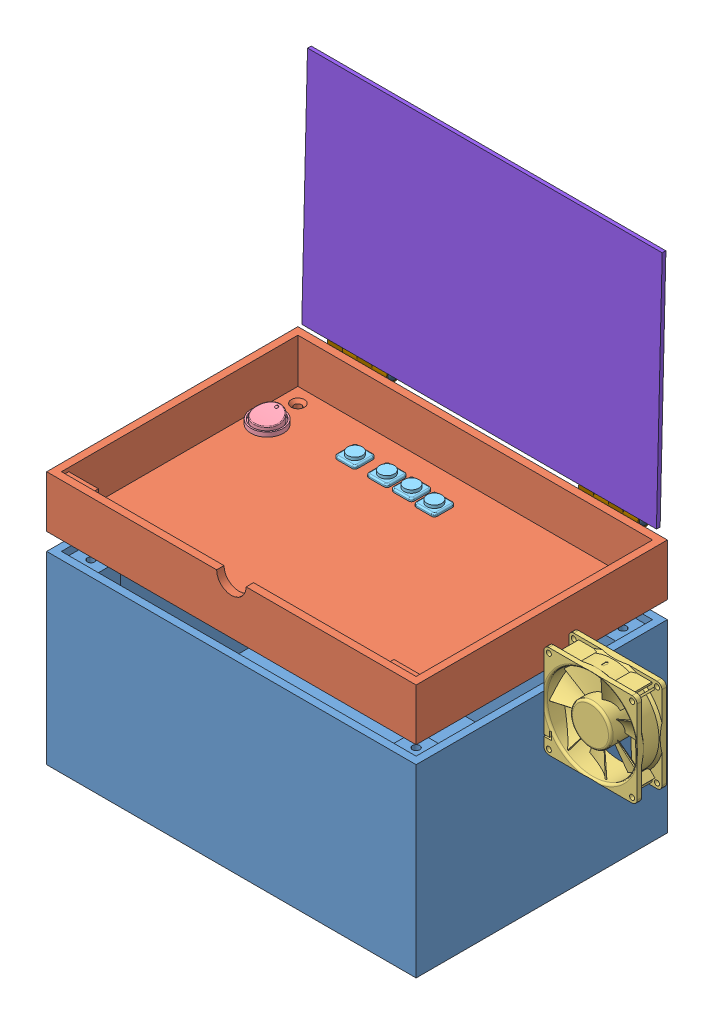
SolidWorks assembly Ground Station, configuration Default. Lengths in mm.
Overall size (498.71 464.43 236.08).
25 component instances, 10 part files, 22 mates.
Components (placement in the parent):
- Box-1: Box [Default] at (130.5013 73.7691 245.9058) size (317.5 158.75 215.9)
- Box Top-1: Box Top [Default] at (130.5013 241.0208 245.9058) size (317.5 50.8 215.9)
- Fan-1: Fan [Default] at (344.3941 242.0632 233.7635) size (80 80 25.71)
- LED Rocker Switch-1: LED Rocker Switch [Default] at (-7.1605 251.1808 185.4528) size (27.94 33 27.94)
- LED Pushbutton-1: LED Pushbutton [Default] at (104.5513 234.6708 173.1134) size (18 29.21 18)
- LED Pushbutton-2: LED Pushbutton [Default] at (83.4333 234.6708 173.1134) size (18 29.21 18)
- LED Pushbutton-3: LED Pushbutton [Default] at (125.7046 234.6708 174.5981) size (18 29.21 18)
- LED Pushbutton-4: LED Pushbutton [Default] at (55.9503 234.6708 173.1134) size (18 29.21 18)
- Green LED-1: Green LED [Default] at (-43.8115 97.7903 137.5598) size (5 11.66 5)
- Green LED-2: Green LED [Default] at (-40.7859 71.4501 137.6368) size (5 11.66 5)
- Green LED-3: Green LED [Default] at (-47.241 141.3846 137.4726) size (5 11.66 5)
- Green LED-4: Green LED [Default] at (-73.5588 134.6358 120.2712) size (5 11.66 5)
- Red LED-1: Red LED [Default] at (-32.75 69.0976 173.2575) size (5 11.66 5)
- Red LED-2: Red LED [Default] at (-48.8212 68.6997 187.7744) size (5 11.66 5)
- Red LED-3: Red LED [Default] at (-85.0237 38.2232 171.227) size (5 11.66 5)
- Red LED-4: Red LED [Default] at (-111.8171 51.6273 156.8365) size (5 11.66 5)
- Acrylic Cover-1: Acrylic Cover [Default] at (130.5013 399.8161 138.5042) x (1 0 0) z (0 0.999704 -0.02434) size (304.8 3.17 203.2)
- Hinge Assembly-1: Hinge Assembly [Default] at (14.4264 255.4915 156.4521) x (1 0 0) z (0 0.999704 -0.02434) size (55.88 13.47 50.95)
  - Hinge Piece-1: Hinge Piece [Default] at (8.1249 17.6047 53.2265) size (50.8 12.7 31.75)
  - Hinge Piece-2: Hinge Piece [Default] at (8.1249 18.0034 20.4703) x (-1 0 0) z (0 0.02434 -0.999704) size (50.8 12.7 31.75)
  - Hinge Pin-1: Hinge Pin [Default] at (-17.2751 23.9547 36.9233) x (0 0 -1) z (1 0 0) size (10.16 10.16 55.88)
- Hinge Assembly-2: Hinge Assembly [Default] at (230.3264 255.4915 156.4521) x (1 0 0) z (0 0.999704 -0.02434) size (55.88 13.47 50.95)
  - Hinge Piece-1: Hinge Piece [Default] at (8.1249 17.6047 53.2265) size (50.8 12.7 31.75)
  - Hinge Piece-2: Hinge Piece [Default] at (8.1249 18.0034 20.4703) x (-1 0 0) z (0 0.02434 -0.999704) size (50.8 12.7 31.75)
  - Hinge Pin-1: Hinge Pin [Default] at (-17.2751 23.9547 36.9233) x (0 0 -1) z (1 0 0) size (10.16 10.16 55.88)
Mates (geometry in assembly coordinates):
- Coincident1: coincident aligned: plane of Box-1 through (289.2513 80.1191 353.8558) normal (0 0 1); plane of Box Top-1 through (289.2513 253.7208 353.8558) normal (0 0 1)
- Coincident2: coincident aligned: plane of Box-1 through (-28.2487 80.1191 353.8558) normal (-1 0 0); plane of Box Top-1 through (-28.2487 253.7208 353.8558) normal (-1 0 0)
- Concentric1: concentric anti-aligned: cylinder of Box Top-1 through (-7.1605 241.0208 185.4528) axis (0 1 0) radius 11.43; cylinder of LED Rocker Switch-1 through (-7.1605 257.5308 185.4528) axis (0 -1 0) radius 13.97
- Parallel1: parallel aligned: plane of Box-1 through (289.2513 80.1191 353.8558) normal (0 0 1); plane of LED Rocker Switch-1 through (-0.0894 243.5608 192.5238) normal (0 0 1)
- Coincident4: coincident anti-aligned: plane of Box Top-1 through (130.5013 253.7208 245.9058) normal (0 1 0); plane of LED Rocker Switch-1 through (-7.1605 253.7208 185.4528) normal (0 -1 0)
- Coincident8: coincident anti-aligned: plane of Box Top-1 through (-21.8987 291.8208 347.5058) normal (1 0 0); plane of Acrylic Cover-1 through (-21.8987 501.3088 132.8572) normal (-1 0 0)
- Coincident15: coincident anti-aligned: plane of Box Top-1 through (289.2513 253.7208 137.9558) normal (0 0 -1); plane of Hinge Assembly-1/Hinge Piece-2 through (22.5513 275.5176 137.9558) normal (0 0 1)
- Coincident16: coincident anti-aligned: plane of Box Top-1 through (289.2513 253.7208 137.9558) normal (0 0 -1); plane of Hinge Assembly-2/Hinge Piece-2 through (238.4513 275.5176 137.9558) normal (0 0 1)
- Coincident17: coincident anti-aligned: plane of Acrylic Cover-1 through (130.5013 399.7389 135.3302) normal (0 -0.02434 -0.999704); plane of Hinge Assembly-2/Hinge Piece-1 through (238.4513 308.2737 137.5571) normal (0 0.02434 0.999704)
- Coincident18: coincident anti-aligned: plane of Acrylic Cover-1 through (130.5013 399.7389 135.3302) normal (0 -0.02434 -0.999704); plane of Hinge Assembly-1/Hinge Piece-1 through (22.5513 308.2737 137.5571) normal (0 0.02434 0.999704)
- Distance2: distance = 25.4 mm aligned: plane of Hinge Assembly-2/Hinge Piece-2 through (263.8513 266.4208 134.7808) normal (1 0 0); plane of Box Top-1 through (289.2513 253.7208 353.8558) normal (1 0 0)
- Distance3: distance = 25.4 mm anti-aligned: plane of Hinge Assembly-1/Hinge Piece-2 through (-2.8487 266.4208 134.7808) normal (0 -1 0); plane of Box Top-1 through (130.5013 291.8208 245.9058) normal (0 1 0)
- Distance4: distance = 25.4 mm aligned: plane of Hinge Assembly-1/Hinge Piece-1 through (-2.8487 317.2906 134.1616) normal (-1 0 0); plane of Box Top-1 through (-28.2487 253.7208 353.8558) normal (-1 0 0)
- Distance6: distance = 6.35 mm: line of Acrylic Cover-1 through (282.9013 298.169 137.8031) axis (-1 0 0); line of Box Top-1 through (289.2513 291.8208 137.9558) axis (-1 0 0)
- Coincident25: coincident anti-aligned: plane of Box Top-1 through (130.5013 253.7208 245.9058) normal (0 1 0); plane of LED Pushbutton-3 through (125.7046 253.7208 174.5981) normal (0 -1 0)
- Coincident26: coincident anti-aligned: plane of Box Top-1 through (130.5013 253.7208 245.9058) normal (0 1 0); plane of LED Pushbutton-1 through (104.5513 253.7208 173.1134) normal (0 -1 0)
- Coincident27: coincident anti-aligned: plane of Box Top-1 through (130.5013 253.7208 245.9058) normal (0 1 0); plane of LED Pushbutton-4 through (55.9503 253.7208 173.1134) normal (0 -1 0)
- Coincident28: coincident anti-aligned: plane of Box Top-1 through (130.5013 253.7208 245.9058) normal (0 1 0); plane of LED Pushbutton-2 through (83.4333 253.7208 173.1134) normal (0 -1 0)
- Concentric2: concentric anti-aligned: cylinder of Box Top-1 through (55.9503 241.0208 173.1134) axis (0 1 0) radius 8; cylinder of LED Pushbutton-4 through (55.9503 253.7208 173.1134) axis (0 -1 0) radius 8
- Concentric3: concentric anti-aligned: cylinder of Box Top-1 through (83.4333 241.0208 173.1134) axis (0 1 0) radius 8; cylinder of LED Pushbutton-2 through (83.4333 253.7208 173.1134) axis (0 -1 0) radius 8
- Concentric4: concentric anti-aligned: cylinder of Box Top-1 through (104.5513 241.0208 173.1134) axis (0 1 0) radius 8; cylinder of LED Pushbutton-1 through (104.5513 253.7208 173.1134) axis (0 -1 0) radius 8
- Concentric5: concentric anti-aligned: cylinder of Box Top-1 through (125.7046 241.0208 174.5981) axis (0 1 0) radius 8; cylinder of LED Pushbutton-3 through (125.7046 253.7208 174.5981) axis (0 -1 0) radius 8
